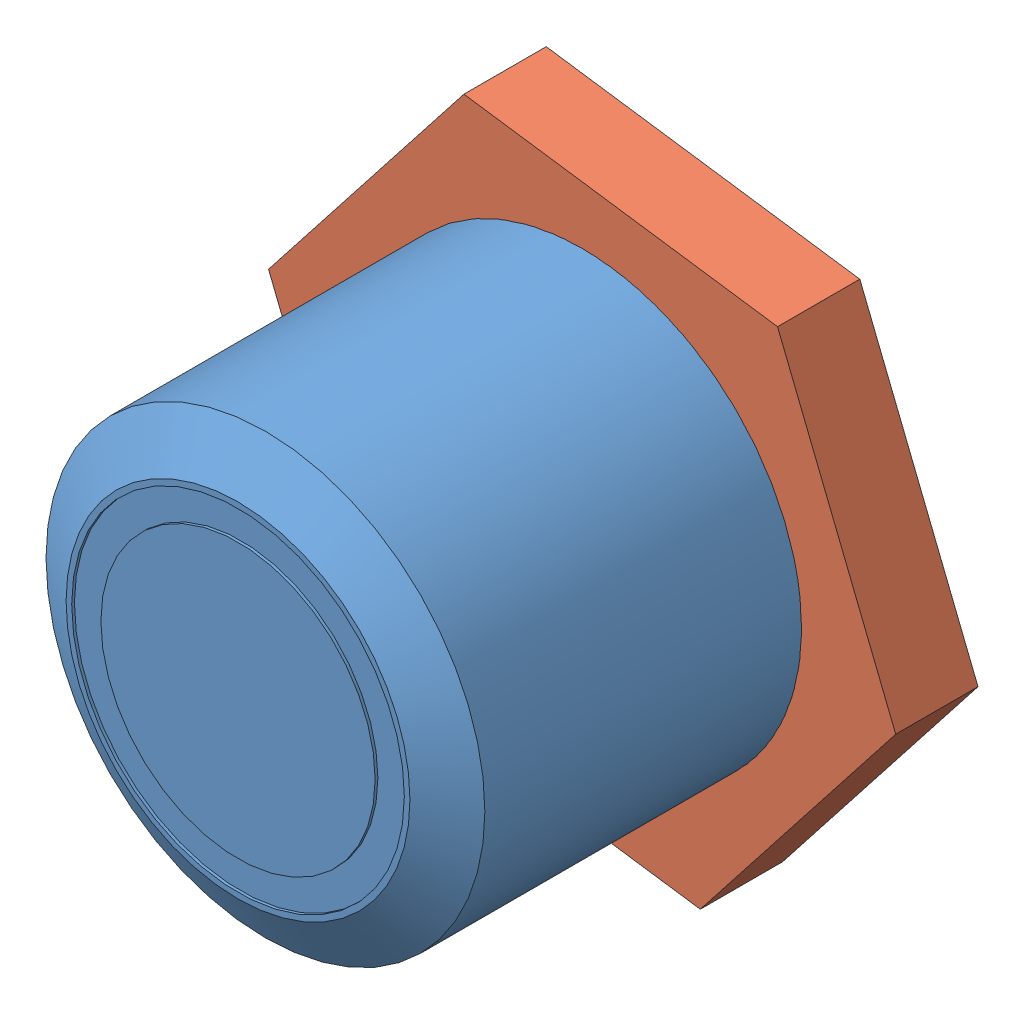
SolidWorks assembly Assem1, configuration Default. Lengths in mm.
Overall size (25.68 26.3 17).
2 component instances, 2 part files, 1 mates.
Components (placement in the parent):
- Button Body-1: Button Body [Default] at (-1.0976 6.3438 -3.7307) size (16 16 17)
- Button Hex Nut-1: Button Hex Nut [Default] at (-1.0976 6.3438 -2.2763) x (0 0 1) z (-0.98279 -0.184727 0) size (3 22.65 21.87)
Mates (geometry in assembly coordinates):
- Coincident1: coincident aligned: cylinder of Button Body-1 through (-1.0976 6.3438 13.2693) axis (0 0 -1) radius 8; circle of Button Hex Nut-1
